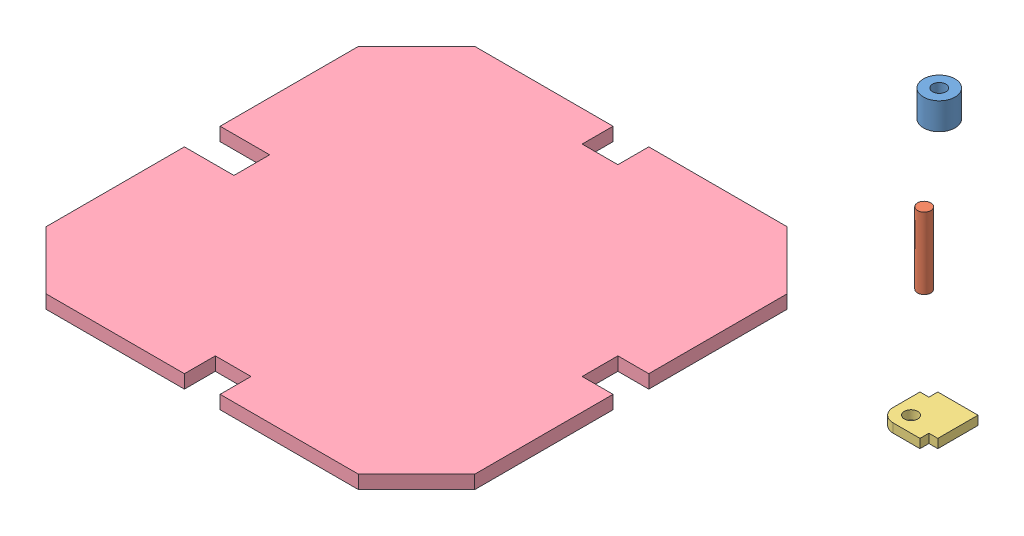
SolidWorks assembly pre print, configuration Default. Lengths in mm.
Overall size (120.65 40.46 125.29).
4 component instances, 4 part files, 0 mates.
Components (placement in the parent):
- spacer-1: spacer [Default] at (-3.3213 34.2058 -20.9414) size (7.07 6 7.07)
- rod-1: rod [Default] at (6.9382 13.1207 -7.3023) size (3 16 3)
- board over hang clips-1: board over hang clips [Default] at (19.6437 -0.2583 5.6675) size (11 2 11)
- Part3-1: Part3 [Default] at (-46.629 19.0044 52.815) size (96 3 96)
